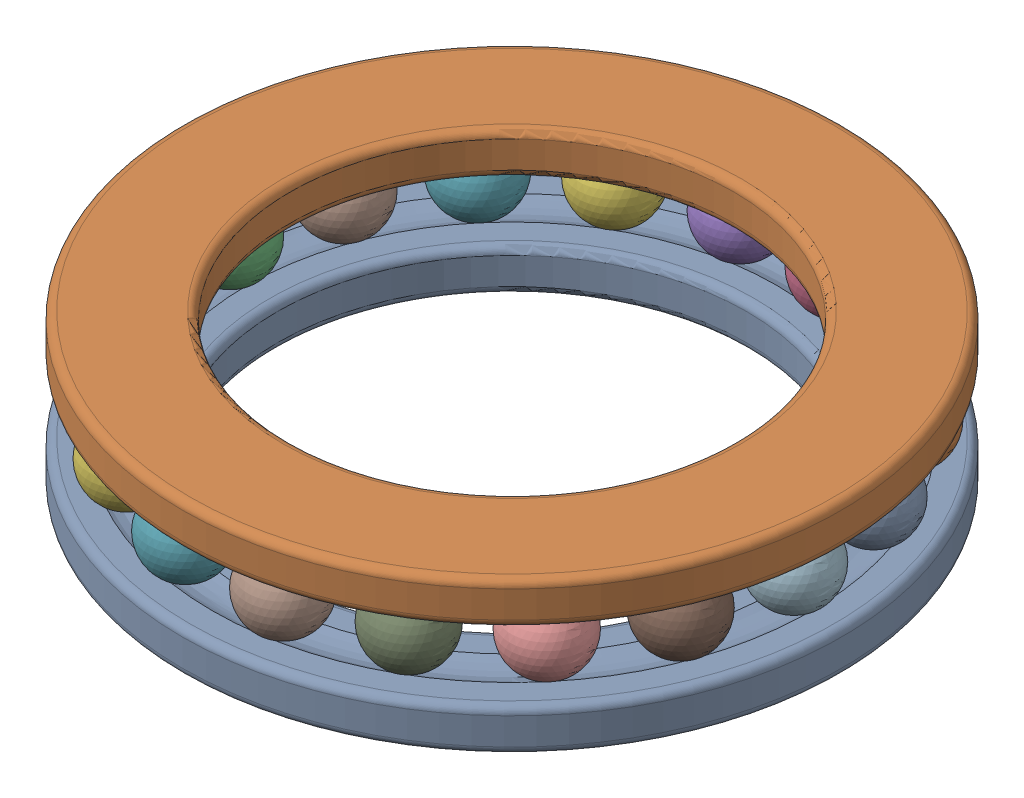
SolidWorks assembly 51107, configuration Default. Lengths in mm.
Overall size (52 12 52).
20 component instances, 3 part files, 0 mates.
Components (placement in the parent):
- 51107 Housing washer-1: 51107 Housing washer [Default] at origin size (52 3.34 52)
- 51107 Shaft washer-1: 51107 Shaft washer [Default] at (0 8.6667 0) x (0 1 0) z (0 0 1) size (3.34 52 52)
- 51107 Ball-1: 51107 Ball [Default] at (-22.25 6 0) x (0 -1 0) z (0 0 1) size (6 6 6)
- 51107 Ball-2: 51107 Ball [Default] at (-20.9082 6 7.6099) x (0 -1 0) z (0 0 1) size (6 6 6)
- 51107 Ball-3: 51107 Ball [Default] at (-17.0445 6 14.302) x (0 -1 0) z (0 0 1) size (6 6 6)
- 51107 Ball-4: 51107 Ball [Default] at (-11.125 6 19.2691) x (0 -1 0) z (0 0 1) size (6 6 6)
- 51107 Ball-5: 51107 Ball [Default] at (-3.8637 6 21.912) x (0 -1 0) z (0 0 1) size (6 6 6)
- 51107 Ball-6: 51107 Ball [Default] at (3.8637 6 21.912) x (0 -1 0) z (0 0 1) size (6 6 6)
- 51107 Ball-7: 51107 Ball [Default] at (11.125 6 19.2691) x (0 -1 0) z (0 0 1) size (6 6 6)
- 51107 Ball-8: 51107 Ball [Default] at (17.0445 6 14.302) x (0 -1 0) z (0 0 1) size (6 6 6)
- 51107 Ball-9: 51107 Ball [Default] at (20.9082 6 7.6099) x (0 -1 0) z (0 0 1) size (6 6 6)
- 51107 Ball-10: 51107 Ball [Default] at (22.25 6 0) x (0 -1 0) z (0 0 1) size (6 6 6)
- 51107 Ball-11: 51107 Ball [Default] at (20.9082 6 -7.6099) x (0 -1 0) z (0 0 1) size (6 6 6)
- 51107 Ball-12: 51107 Ball [Default] at (17.0445 6 -14.302) x (0 -1 0) z (0 0 1) size (6 6 6)
- 51107 Ball-13: 51107 Ball [Default] at (11.125 6 -19.2691) x (0 -1 0) z (0 0 1) size (6 6 6)
- 51107 Ball-14: 51107 Ball [Default] at (3.8637 6 -21.912) x (0 -1 0) z (0 0 1) size (6 6 6)
- 51107 Ball-15: 51107 Ball [Default] at (-3.8637 6 -21.912) x (0 -1 0) z (0 0 1) size (6 6 6)
- 51107 Ball-16: 51107 Ball [Default] at (-11.125 6 -19.2691) x (0 -1 0) z (0 0 1) size (6 6 6)
- 51107 Ball-17: 51107 Ball [Default] at (-17.0445 6 -14.302) x (0 -1 0) z (0 0 1) size (6 6 6)
- 51107 Ball-18: 51107 Ball [Default] at (-20.9082 6 -7.6099) x (0 -1 0) z (0 0 1) size (6 6 6)
